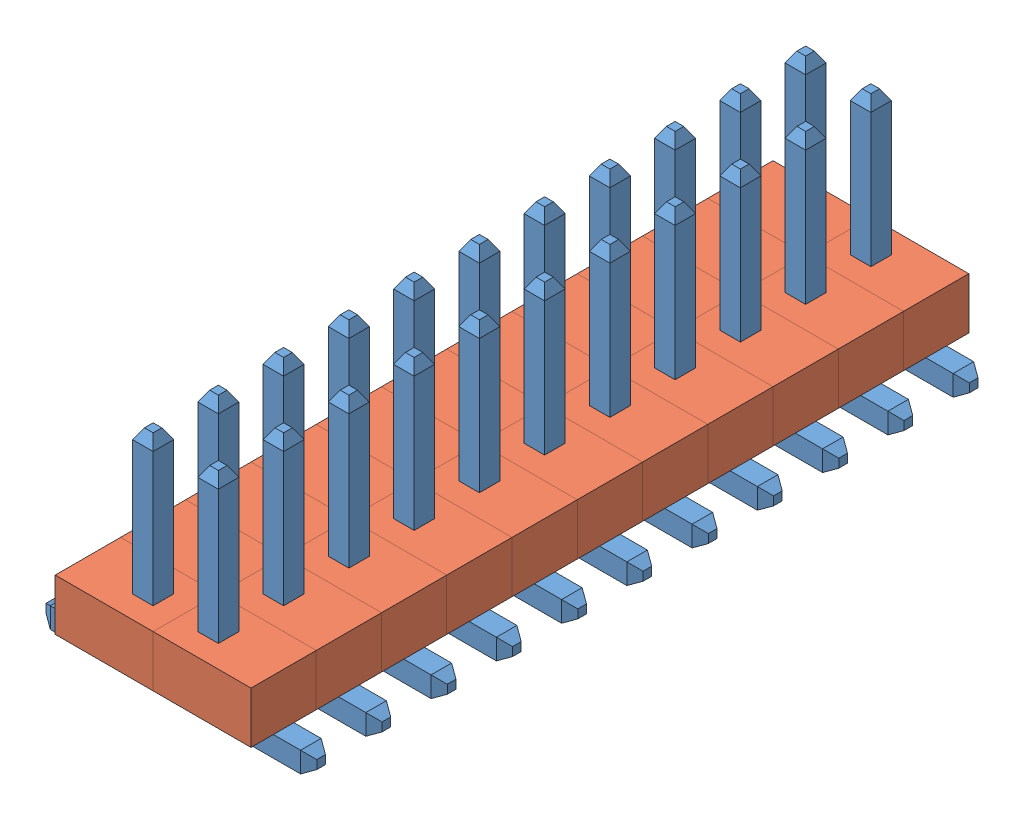
SolidWorks assembly Assem6, configuration Default. Lengths in mm.
Overall size (5.27 4.2 13.97).
66 component instances, 2 part files, 0 mates.
Components (placement in the parent):
- 1_27mm_single_pin_assembled-1: 1_27mm_single_pin_assembled [Default] at (-0.2217 -0.1756 0.351) size (2.64 4.2 1.27)
  - 1_27mm_pin_right_angle-1: 1_27mm_pin_right_angle [Default] at (-0.7701 -1.6572 -0.2335) size (2.2 4.2 0.4)
  - 1_27mm_plastic_for_pin-1: 1_27mm_plastic_for_pin [Default] at (-0.4526 -1.4572 -0.2335) x (0 0 -1) z (1 0 0) size (1.27 1 1.91)
- 1_27mm_single_pin_assembled-2: 1_27mm_single_pin_assembled [Default] at (-0.2217 -0.1756 -0.919) size (2.64 4.2 1.27)
  - 1_27mm_pin_right_angle-1: 1_27mm_pin_right_angle [Default] at (-0.7701 -1.6572 -0.2335) size (2.2 4.2 0.4)
  - 1_27mm_plastic_for_pin-1: 1_27mm_plastic_for_pin [Default] at (-0.4526 -1.4572 -0.2335) x (0 0 -1) z (1 0 0) size (1.27 1 1.91)
- 1_27mm_single_pin_assembled-3: 1_27mm_single_pin_assembled [Default] at (-0.2217 -0.1756 -2.189) size (2.64 4.2 1.27)
  - 1_27mm_pin_right_angle-1: 1_27mm_pin_right_angle [Default] at (-0.7701 -1.6572 -0.2335) size (2.2 4.2 0.4)
  - 1_27mm_plastic_for_pin-1: 1_27mm_plastic_for_pin [Default] at (-0.4526 -1.4572 -0.2335) x (0 0 -1) z (1 0 0) size (1.27 1 1.91)
- 1_27mm_single_pin_assembled-4: 1_27mm_single_pin_assembled [Default] at (-0.2217 -0.1756 -3.459) size (2.64 4.2 1.27)
  - 1_27mm_pin_right_angle-1: 1_27mm_pin_right_angle [Default] at (-0.7701 -1.6572 -0.2335) size (2.2 4.2 0.4)
  - 1_27mm_plastic_for_pin-1: 1_27mm_plastic_for_pin [Default] at (-0.4526 -1.4572 -0.2335) x (0 0 -1) z (1 0 0) size (1.27 1 1.91)
- 1_27mm_single_pin_assembled-5: 1_27mm_single_pin_assembled [Default] at (-0.2217 -0.1756 -4.729) size (2.64 4.2 1.27)
  - 1_27mm_pin_right_angle-1: 1_27mm_pin_right_angle [Default] at (-0.7701 -1.6572 -0.2335) size (2.2 4.2 0.4)
  - 1_27mm_plastic_for_pin-1: 1_27mm_plastic_for_pin [Default] at (-0.4526 -1.4572 -0.2335) x (0 0 -1) z (1 0 0) size (1.27 1 1.91)
- 1_27mm_single_pin_assembled-6: 1_27mm_single_pin_assembled [Default] at (-0.2217 -0.1756 -5.999) size (2.64 4.2 1.27)
  - 1_27mm_pin_right_angle-1: 1_27mm_pin_right_angle [Default] at (-0.7701 -1.6572 -0.2335) size (2.2 4.2 0.4)
  - 1_27mm_plastic_for_pin-1: 1_27mm_plastic_for_pin [Default] at (-0.4526 -1.4572 -0.2335) x (0 0 -1) z (1 0 0) size (1.27 1 1.91)
- 1_27mm_single_pin_assembled-7: 1_27mm_single_pin_assembled [Default] at (-0.2217 -0.1756 -7.269) size (2.64 4.2 1.27)
  - 1_27mm_pin_right_angle-1: 1_27mm_pin_right_angle [Default] at (-0.7701 -1.6572 -0.2335) size (2.2 4.2 0.4)
  - 1_27mm_plastic_for_pin-1: 1_27mm_plastic_for_pin [Default] at (-0.4526 -1.4572 -0.2335) x (0 0 -1) z (1 0 0) size (1.27 1 1.91)
- 1_27mm_single_pin_assembled-8: 1_27mm_single_pin_assembled [Default] at (-0.2217 -0.1756 -8.539) size (2.64 4.2 1.27)
  - 1_27mm_pin_right_angle-1: 1_27mm_pin_right_angle [Default] at (-0.7701 -1.6572 -0.2335) size (2.2 4.2 0.4)
  - 1_27mm_plastic_for_pin-1: 1_27mm_plastic_for_pin [Default] at (-0.4526 -1.4572 -0.2335) x (0 0 -1) z (1 0 0) size (1.27 1 1.91)
- 1_27mm_single_pin_assembled-9: 1_27mm_single_pin_assembled [Default] at (-0.2217 -0.1756 -9.809) size (2.64 4.2 1.27)
  - 1_27mm_pin_right_angle-1: 1_27mm_pin_right_angle [Default] at (-0.7701 -1.6572 -0.2335) size (2.2 4.2 0.4)
  - 1_27mm_plastic_for_pin-1: 1_27mm_plastic_for_pin [Default] at (-0.4526 -1.4572 -0.2335) x (0 0 -1) z (1 0 0) size (1.27 1 1.91)
- 1_27mm_single_pin_assembled-10: 1_27mm_single_pin_assembled [Default] at (-0.2217 -0.1756 -11.079) size (2.64 4.2 1.27)
  - 1_27mm_pin_right_angle-1: 1_27mm_pin_right_angle [Default] at (-0.7701 -1.6572 -0.2335) size (2.2 4.2 0.4)
  - 1_27mm_plastic_for_pin-1: 1_27mm_plastic_for_pin [Default] at (-0.4526 -1.4572 -0.2335) x (0 0 -1) z (1 0 0) size (1.27 1 1.91)
- 1_27mm_single_pin_assembled-11: 1_27mm_single_pin_assembled [Default] at (-0.2217 -0.1756 -12.349) size (2.64 4.2 1.27)
  - 1_27mm_pin_right_angle-1: 1_27mm_pin_right_angle [Default] at (-0.7701 -1.6572 -0.2335) size (2.2 4.2 0.4)
  - 1_27mm_plastic_for_pin-1: 1_27mm_plastic_for_pin [Default] at (-0.4526 -1.4572 -0.2335) x (0 0 -1) z (1 0 0) size (1.27 1 1.91)
- 1_27mm_single_pin_assembled-12: 1_27mm_single_pin_assembled [Default] at (-3.0319 -0.1756 -12.816) x (-1 0 0) z (0 0 -1) size (2.64 4.2 1.27)
  - 1_27mm_pin_right_angle-1: 1_27mm_pin_right_angle [Default] at (-0.7701 -1.6572 -0.2335) size (2.2 4.2 0.4)
  - 1_27mm_plastic_for_pin-1: 1_27mm_plastic_for_pin [Default] at (-0.4526 -1.4572 -0.2335) x (0 0 -1) z (1 0 0) size (1.27 1 1.91)
- 1_27mm_single_pin_assembled-13: 1_27mm_single_pin_assembled [Default] at (-3.0319 -0.1756 -11.546) x (-1 0 0) z (0 0 -1) size (2.64 4.2 1.27)
  - 1_27mm_pin_right_angle-1: 1_27mm_pin_right_angle [Default] at (-0.7701 -1.6572 -0.2335) size (2.2 4.2 0.4)
  - 1_27mm_plastic_for_pin-1: 1_27mm_plastic_for_pin [Default] at (-0.4526 -1.4572 -0.2335) x (0 0 -1) z (1 0 0) size (1.27 1 1.91)
- 1_27mm_single_pin_assembled-14: 1_27mm_single_pin_assembled [Default] at (-3.0319 -0.1756 -10.276) x (-1 0 0) z (0 0 -1) size (2.64 4.2 1.27)
  - 1_27mm_pin_right_angle-1: 1_27mm_pin_right_angle [Default] at (-0.7701 -1.6572 -0.2335) size (2.2 4.2 0.4)
  - 1_27mm_plastic_for_pin-1: 1_27mm_plastic_for_pin [Default] at (-0.4526 -1.4572 -0.2335) x (0 0 -1) z (1 0 0) size (1.27 1 1.91)
- 1_27mm_single_pin_assembled-15: 1_27mm_single_pin_assembled [Default] at (-3.0319 -0.1756 -9.006) x (-1 0 0) z (0 0 -1) size (2.64 4.2 1.27)
  - 1_27mm_pin_right_angle-1: 1_27mm_pin_right_angle [Default] at (-0.7701 -1.6572 -0.2335) size (2.2 4.2 0.4)
  - 1_27mm_plastic_for_pin-1: 1_27mm_plastic_for_pin [Default] at (-0.4526 -1.4572 -0.2335) x (0 0 -1) z (1 0 0) size (1.27 1 1.91)
- 1_27mm_single_pin_assembled-16: 1_27mm_single_pin_assembled [Default] at (-3.0319 -0.1756 -7.736) x (-1 0 0) z (0 0 -1) size (2.64 4.2 1.27)
  - 1_27mm_pin_right_angle-1: 1_27mm_pin_right_angle [Default] at (-0.7701 -1.6572 -0.2335) size (2.2 4.2 0.4)
  - 1_27mm_plastic_for_pin-1: 1_27mm_plastic_for_pin [Default] at (-0.4526 -1.4572 -0.2335) x (0 0 -1) z (1 0 0) size (1.27 1 1.91)
- 1_27mm_single_pin_assembled-17: 1_27mm_single_pin_assembled [Default] at (-3.0319 -0.1756 -6.466) x (-1 0 0) z (0 0 -1) size (2.64 4.2 1.27)
  - 1_27mm_pin_right_angle-1: 1_27mm_pin_right_angle [Default] at (-0.7701 -1.6572 -0.2335) size (2.2 4.2 0.4)
  - 1_27mm_plastic_for_pin-1: 1_27mm_plastic_for_pin [Default] at (-0.4526 -1.4572 -0.2335) x (0 0 -1) z (1 0 0) size (1.27 1 1.91)
- 1_27mm_single_pin_assembled-18: 1_27mm_single_pin_assembled [Default] at (-3.0319 -0.1756 -5.196) x (-1 0 0) z (0 0 -1) size (2.64 4.2 1.27)
  - 1_27mm_pin_right_angle-1: 1_27mm_pin_right_angle [Default] at (-0.7701 -1.6572 -0.2335) size (2.2 4.2 0.4)
  - 1_27mm_plastic_for_pin-1: 1_27mm_plastic_for_pin [Default] at (-0.4526 -1.4572 -0.2335) x (0 0 -1) z (1 0 0) size (1.27 1 1.91)
- 1_27mm_single_pin_assembled-19: 1_27mm_single_pin_assembled [Default] at (-3.0319 -0.1756 -3.926) x (-1 0 0) z (0 0 -1) size (2.64 4.2 1.27)
  - 1_27mm_pin_right_angle-1: 1_27mm_pin_right_angle [Default] at (-0.7701 -1.6572 -0.2335) size (2.2 4.2 0.4)
  - 1_27mm_plastic_for_pin-1: 1_27mm_plastic_for_pin [Default] at (-0.4526 -1.4572 -0.2335) x (0 0 -1) z (1 0 0) size (1.27 1 1.91)
- 1_27mm_single_pin_assembled-20: 1_27mm_single_pin_assembled [Default] at (-3.0319 -0.1756 -2.656) x (-1 0 0) z (0 0 -1) size (2.64 4.2 1.27)
  - 1_27mm_pin_right_angle-1: 1_27mm_pin_right_angle [Default] at (-0.7701 -1.6572 -0.2335) size (2.2 4.2 0.4)
  - 1_27mm_plastic_for_pin-1: 1_27mm_plastic_for_pin [Default] at (-0.4526 -1.4572 -0.2335) x (0 0 -1) z (1 0 0) size (1.27 1 1.91)
- 1_27mm_single_pin_assembled-21: 1_27mm_single_pin_assembled [Default] at (-3.0319 -0.1756 -0.116) x (-1 0 0) z (0 0 -1) size (2.64 4.2 1.27)
  - 1_27mm_pin_right_angle-1: 1_27mm_pin_right_angle [Default] at (-0.7701 -1.6572 -0.2335) size (2.2 4.2 0.4)
  - 1_27mm_plastic_for_pin-1: 1_27mm_plastic_for_pin [Default] at (-0.4526 -1.4572 -0.2335) x (0 0 -1) z (1 0 0) size (1.27 1 1.91)
- 1_27mm_single_pin_assembled-22: 1_27mm_single_pin_assembled [Default] at (-3.0319 -0.1756 -1.386) x (-1 0 0) z (0 0 -1) size (2.64 4.2 1.27)
  - 1_27mm_pin_right_angle-1: 1_27mm_pin_right_angle [Default] at (-0.7701 -1.6572 -0.2335) size (2.2 4.2 0.4)
  - 1_27mm_plastic_for_pin-1: 1_27mm_plastic_for_pin [Default] at (-0.4526 -1.4572 -0.2335) x (0 0 -1) z (1 0 0) size (1.27 1 1.91)
